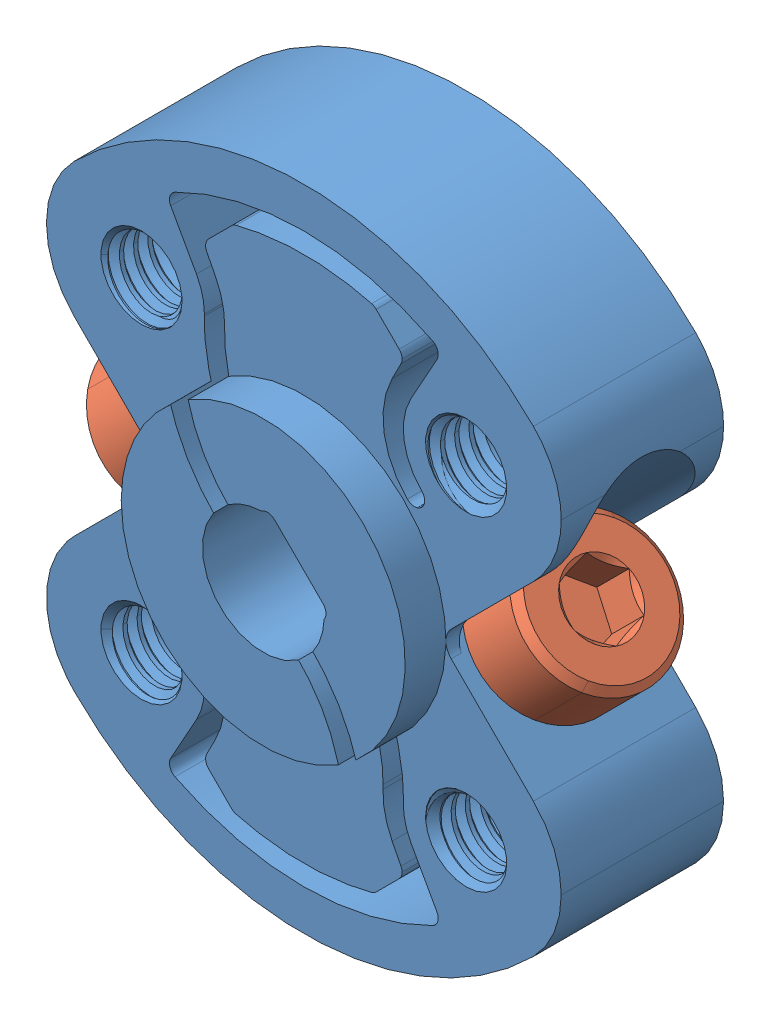
SolidWorks assembly 6mm D-bore Hub 1309-0016-1006, configuration Default. Lengths in mm.
Overall size (28.36 32 10.95).
3 component instances, 2 part files, 0 mates.
Components (placement in the parent):
- 1309-0016-1006.STEP-1: 1309-0016-1006.STEP [Default] at (-18.2019 0.5776 8.7736) size (25.38 32 10)
- 2800-0004-0014_90128A207.STEP-1: 2800-0004-0014_90128A207.STEP [Default] at (-16.149 11.6963 8.7736) x (0.5 -0.5 -0.707107) z (0.707107 0.707107 0) size (7 7 18.01)
- 2800-0004-0014_90128A207.STEP-2: 2800-0004-0014_90128A207.STEP [Default] at (-20.2547 -10.5411 8.7736) x (-0.5 0.5 -0.707107) z (-0.707107 -0.707107 0) size (7 7 18.01)
